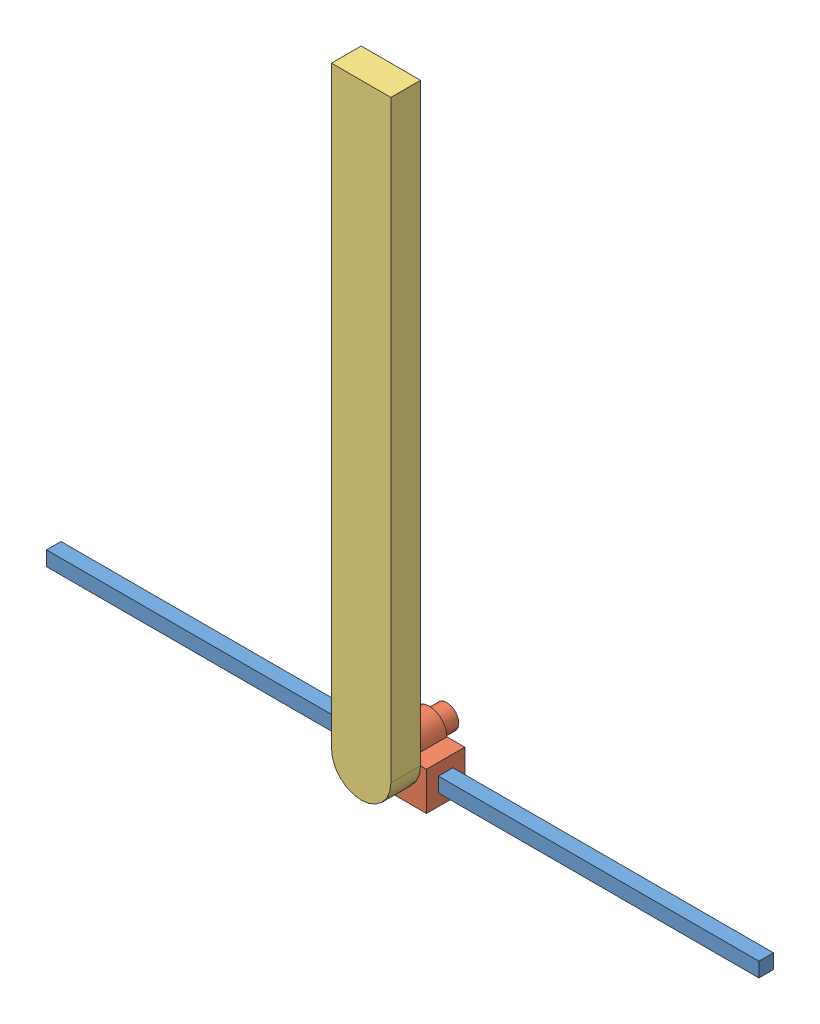
SolidWorks assembly daolibai, configuration Default. Lengths in mm.
Overall size (1200 1064.5 144.5).
3 component instances, 3 part files, 4 mates.
Components (placement in the parent):
- daogui-1: daogui [Default] at (100.1319 110.4241 206.6142) size (1200 24.5 24.5)
- huakuai-1: huakuai [Default] at (100.1319 110.4241 206.6142) size (120 94.5 124.5)
- baigan-1: baigan [Default] at (100.1319 154.9241 288.8642) x (0 1 0) z (0 0 -1) size (1050 100 50)
Mates (geometry in assembly coordinates):
- 重合1: coincident anti-aligned: plane of daogui-1 through (-499.8681 134.9241 194.3642) normal (0 0 -1); plane of huakuai-1 through (40.1319 110.4241 194.3642) normal (0 0 1)
- 重合2: coincident anti-aligned: plane of daogui-1 through (100.1319 134.9241 206.6142) normal (0 1 0); plane of huakuai-1 through (40.1319 134.9241 218.8642) normal (0 -1 0)
- 同心1: concentric aligned: cylinder of huakuai-1 through (100.1319 154.9241 268.8642) axis (0 0 -1) radius 20; cylinder of baigan-1 through (100.1319 154.9241 268.8642) axis (0 0 -1) radius 20
- 重合3: coincident anti-aligned: plane of huakuai-1 through (40.1319 154.9241 238.8642) normal (0 0 1); plane of baigan-1 through (100.1319 154.9241 238.8642) normal (0 0 -1)
